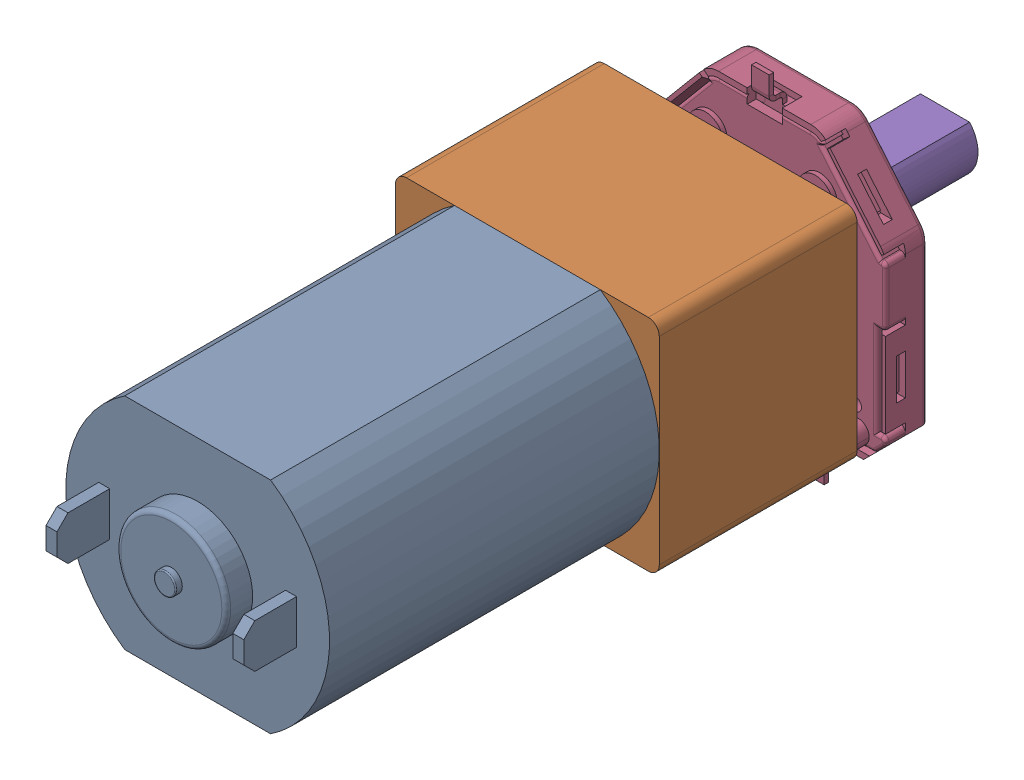
SolidWorks assembly all, configuration 默认. Lengths in mm.
Overall size (12 14.9 36.4).
5 component instances, 5 part files, 12 mates.
Components (placement in the parent):
- n20_motor-1: n20_motor [默认] at (0.0455 -2.532 -8.7) size (12 10 17.5)
- gear_box-2: gear_box [默认] at (0.0455 -2.532 -8.7) x (1 0 0) z (0 0 -1) size (12 10 9.8)
- middle-1: middle [默认] at (0.0455 -2.532 -22.2) size (4 3 3.5)
- SV01A_smd-2: SV01A_smd [默认] at (-54.3126 -3.0818 -21.395) x (-1 0 0) z (0 0 -1) size (11 14.9 3.15)
- n20_gearbox_shaft-1: n20_gearbox_shaft [默认] at (0.0455 -2.532 -17.7) x (-1 0 0) z (0 0 -1) size (3 3 10)
Mates (geometry in assembly coordinates):
- 重合10: coincident anti-aligned: plane of n20_motor-1 through (0.0455 -2.532 -8.7) normal (0 0 -1); plane of gear_box-2 through (0.0455 -2.532 -8.7) normal (0 0 1)
- 同心2: concentric aligned: circle of gear_box-2; circle of SV01A_smd-2
- 重合23: coincident anti-aligned: plane of SV01A_smd-2 through (0.0455 -2.532 -18.7) normal (0 0 1); plane of n20_gearbox_shaft-1 through (0.0455 -2.532 -18.7) normal (0 0 -1)
- 同心3: concentric anti-aligned: circle of n20_motor-1; circle of gear_box-2
- 同心4: concentric aligned: circle of gear_box-2; circle of n20_gearbox_shaft-1
- 重合19: coincident anti-aligned: plane of gear_box-2 through (0.0455 -2.532 -17.7) normal (0 0 -1); plane of n20_gearbox_shaft-1 through (0.0455 -2.532 -17.7) normal (0 0 1)
- 重合20: coincident anti-aligned: plane of SV01A_smd-2 through (1.7775 -1.532 -18.955) normal (0 -1 0); plane of n20_gearbox_shaft-1 through (1.1635 -1.532 -18.7) normal (0 1 0)
- 同心5: concentric anti-aligned: circle of middle-1; circle of SV01A_smd-2
- 重合21: coincident anti-aligned: plane of middle-1 through (0.0455 -1.532 -18.7) normal (0 1 0); plane of SV01A_smd-2 through (1.7775 -1.532 -18.955) normal (0 -1 0)
- 重合22: coincident aligned: plane of middle-1 through (0.0455 -2.532 -18.7) normal (0 0 1); plane of SV01A_smd-2 through (0.0455 -2.532 -18.7) normal (0 0 1)
- 重合25: coincident aligned: plane of n20_motor-1 through (3.3621 2.468 6.3) normal (0 1 0); plane of gear_box-2 through (-5.9545 2.468 -17.7) normal (0 1 0)
- 平行5: parallel aligned: plane of n20_motor-1 through (3.3621 -7.532 6.3) normal (0 -1 0); plane of SV01A_smd-2 through (-4.4545 -9.032 -19.495) normal (0 -1 0)
